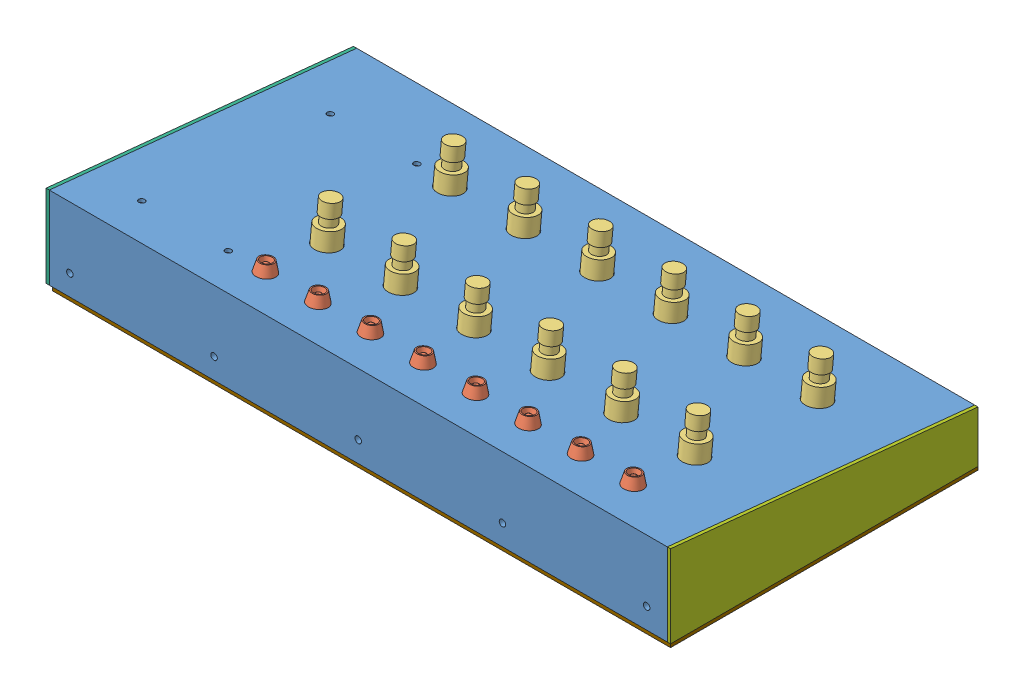
SolidWorks assembly case, configuration Défaut. Lengths in mm.
Overall size (305.42 59.42 149.25).
30 component instances, 9 part files, 75 mates.
Components (placement in the parent):
- top-1: top [Défaut] at (-137.6101 7.1938 300) size (300 40 149.25)
- led_red-1: led_red [Défaut] at (74.8899 20.7656 306.4982) x (-0.818284 -0.057481 -0.571933) z (0 0.994987 -0.1) size (9.2 9.2 35)
- led_red-2: led_red [Défaut] at (125.8899 20.7656 306.4982) x (-0.818284 -0.057481 -0.571933) z (0 0.994987 -0.1) size (9.2 9.2 35)
- led_red-3: led_red [Défaut] at (-27.1101 20.7656 306.4982) x (-0.818284 -0.057481 -0.571933) z (0 0.994987 -0.1) size (9.2 9.2 35)
- led_red-4: led_red [Défaut] at (-1.6101 20.7656 306.4982) x (-0.818284 -0.057481 -0.571933) z (0 0.994987 -0.1) size (9.2 9.2 35)
- led_red-5: led_red [Défaut] at (-52.6101 20.7656 306.4982) x (-0.818284 -0.057481 -0.571933) z (0 0.994987 -0.1) size (9.2 9.2 35)
- led_red-6: led_red [Défaut] at (49.3899 20.7656 306.4982) x (-0.818284 -0.057481 -0.571933) z (0 0.994987 -0.1) size (9.2 9.2 35)
- led_red-7: led_red [Défaut] at (100.3899 20.7656 306.4982) x (-0.818284 -0.057481 -0.571933) z (0 0.994987 -0.1) size (9.2 9.2 35)
- led_red-8: led_red [Défaut] at (23.8899 20.7656 306.4982) x (-0.818284 -0.057481 -0.571933) z (0 0.994987 -0.1) size (9.2 9.2 35)
- sw-1: sw [Défaut] at (125.8899 16.5526 280.454) x (1 0 0) z (0 -0.994987 0.1) size (13.3 30.3 33.85)
- sw-2: sw [Défaut] at (54.4899 10.5526 220.7547) x (1 0 0) z (0 -0.994987 0.1) size (13.3 30.3 33.85)
- sw-3: sw [Défaut] at (-16.9101 16.5526 280.454) x (1 0 0) z (0 -0.994987 0.1) size (13.3 30.3 33.85)
- sw-4: sw [Défaut] at (54.4899 16.5526 280.454) x (1 0 0) z (0 -0.994987 0.1) size (13.3 30.3 33.85)
- sw-5: sw [Défaut] at (90.1899 10.5526 220.7547) x (1 0 0) z (0 -0.994987 0.1) size (13.3 30.3 33.85)
- sw-6: sw [Défaut] at (-52.6101 16.5526 280.454) x (1 0 0) z (0 -0.994987 0.1) size (13.3 30.3 33.85)
- sw-7: sw [Défaut] at (90.1899 16.5526 280.454) x (1 0 0) z (0 -0.994987 0.1) size (13.3 30.3 33.85)
- sw-8: sw [Défaut] at (18.7899 10.5526 220.7547) x (1 0 0) z (0 -0.994987 0.1) size (13.3 30.3 33.85)
- sw-9: sw [Défaut] at (125.8899 10.5526 220.7547) x (1 0 0) z (0 -0.994987 0.1) size (13.3 30.3 33.85)
- sw-10: sw [Défaut] at (18.7899 16.5526 280.454) x (1 0 0) z (0 -0.994987 0.1) size (13.3 30.3 33.85)
- sw-11: sw [Défaut] at (-16.9101 10.5526 220.7547) x (1 0 0) z (0 -0.994987 0.1) size (13.3 30.3 33.85)
- sw-12: sw [Défaut] at (-52.6101 10.5526 220.7547) x (1 0 0) z (0 -0.994987 0.1) size (13.3 30.3 33.85)
- standoff_m3_10mm-1: standoff_m3_10mm [Défaut] at (-112.6101 9.9861 215.1181) x (1 0 0) z (0 -0.994987 0.1) size (5.2 4.5 10)
- standoff_m3_10mm-2: standoff_m3_10mm [Défaut] at (-112.6101 19.1861 306.657) x (1 0 0) z (0 -0.994987 0.1) size (5.2 4.5 10)
- standoff_m3_10mm-3: standoff_m3_10mm [Défaut] at (-70.6101 19.1861 306.657) x (1 0 0) z (0 -0.994987 0.1) size (5.2 4.5 10)
- standoff_m3_10mm-4: standoff_m3_10mm [Défaut] at (-70.6101 9.9861 215.1181) x (1 0 0) z (0 -0.994987 0.1) size (5.2 4.5 10)
- pcb-1: pcb [Défaut] at (-91.6101 4.6362 261.8875) x (0 -0.1 -0.994987) z (0 -0.994987 0.1) size (100 50 21.6)
- side_right-1: side_right [Défaut] at (-139.1976 -17.2344 177.1499) x (0 0 -1) z (1 0 0) size (149.25 40 1.59)
- side_left-1: side_left [Défaut] at (162.3899 -17.2344 177.1499) x (0 0 -1) z (1 0 0) size (149.25 40 1.59)
- dsub-9-1: dsub-9 [Défaut] at (-165.0011 -8.2344 294.9048) x (0 0 -1) z (1 0 0) size (30.81 12.55 16.87)
- bottom-1: bottom [Défaut] at (-3.6127 -18.8219 253.4547) x (1 0 0) z (0 1 0) size (300 149.25 1.59)
Mates (geometry in assembly coordinates):
- Coïncidente1: coincident: plane of led_red-4 through (-1.6101 20.7656 306.4982) normal (0 -0.994987 0.1); plane of led_red-5 through (-52.6101 20.7656 306.4982) normal (0 -0.994987 0.1)
- Coïncidente2: coincident: plane of led_red-3 through (-27.1101 20.7656 306.4982) normal (0 -0.994987 0.1); plane of led_red-5 through (-52.6101 20.7656 306.4982) normal (0 -0.994987 0.1)
- Coïncidente3: coincident: plane of led_red-1 through (74.8899 20.7656 306.4982) normal (0 -0.994987 0.1); plane of led_red-5 through (-52.6101 20.7656 306.4982) normal (0 -0.994987 0.1)
- Coïncidente4: coincident: plane of led_red-2 through (125.8899 20.7656 306.4982) normal (0 -0.994987 0.1); plane of led_red-5 through (-52.6101 20.7656 306.4982) normal (0 -0.994987 0.1)
- Coïncidente5: coincident: plane of led_red-5 through (-52.6101 20.7656 306.4982) normal (0 -0.994987 0.1); plane of led_red-6 through (49.3899 20.7656 306.4982) normal (0 -0.994987 0.1)
- Coïncidente6: coincident: plane of led_red-5 through (-52.6101 20.7656 306.4982) normal (0 -0.994987 0.1); plane of led_red-7 through (100.3899 20.7656 306.4982) normal (0 -0.994987 0.1)
- Coïncidente7: coincident: plane of led_red-5 through (-52.6101 20.7656 306.4982) normal (0 -0.994987 0.1); plane of led_red-8 through (23.8899 20.7656 306.4982) normal (0 -0.994987 0.1)
- Coïncidente8: coincident: plane of top-1 through (162.3899 22.7656 326.398) normal (0 0.994987 -0.1); plane of led_red-5 through (-52.6101 20.7656 306.4982) normal (0 -0.994987 0.1)
- Coaxiale1: concentric: cylinder of top-1 through (-52.6101 -18.8355 310.4783) axis (0 0.994987 -0.1) radius 4; cylinder of led_red-5 through (-52.6101 -9.084 309.4982) axis (0 0.994987 -0.1) radius 3.85
- Coaxiale2: concentric: cylinder of top-1 through (-27.1101 -18.8355 310.4783) axis (0 0.994987 -0.1) radius 4; cylinder of led_red-3 through (-27.1101 -9.084 309.4982) axis (0 0.994987 -0.1) radius 3.85
- Coaxiale3: concentric: cylinder of top-1 through (-1.6101 -18.8355 310.4783) axis (0 0.994987 -0.1) radius 4; cylinder of led_red-4 through (-1.6101 -9.084 309.4982) axis (0 0.994987 -0.1) radius 3.85
- Coaxiale4: concentric: cylinder of top-1 through (23.8899 -18.8355 310.4783) axis (0 0.994987 -0.1) radius 4; cylinder of led_red-8 through (23.8899 -9.084 309.4982) axis (0 0.994987 -0.1) radius 3.85
- Coaxiale5: concentric: cylinder of top-1 through (49.3899 -18.8355 310.4783) axis (0 0.994987 -0.1) radius 4; cylinder of led_red-6 through (49.3899 -9.084 309.4982) axis (0 0.994987 -0.1) radius 3.85
- Coaxiale6: concentric: cylinder of top-1 through (74.8899 -18.8355 310.4783) axis (0 0.994987 -0.1) radius 4; cylinder of led_red-1 through (74.8899 -9.084 309.4982) axis (0 0.994987 -0.1) radius 3.85
- Coaxiale7: concentric: cylinder of top-1 through (100.3899 -18.8355 310.4783) axis (0 0.994987 -0.1) radius 4; cylinder of led_red-7 through (100.3899 -9.084 309.4982) axis (0 0.994987 -0.1) radius 3.85
- Coaxiale8: concentric: cylinder of top-1 through (125.8899 -18.8355 310.4783) axis (0 0.994987 -0.1) radius 4; cylinder of led_red-2 through (125.8899 -9.084 309.4982) axis (0 0.994987 -0.1) radius 3.85
- Coïncidente9: coincident: plane of sw-1 through (125.8899 16.5526 280.454) normal (0 0.994987 -0.1); plane of sw-2 through (54.4899 10.5526 220.7547) normal (0 0.994987 -0.1)
- Coïncidente10: coincident: plane of sw-1 through (125.8899 16.5526 280.454) normal (0 0.994987 -0.1); plane of sw-3 through (-16.9101 16.5526 280.454) normal (0 0.994987 -0.1)
- Coïncidente11: coincident: plane of sw-1 through (125.8899 16.5526 280.454) normal (0 0.994987 -0.1); plane of sw-4 through (54.4899 16.5526 280.454) normal (0 0.994987 -0.1)
- Coïncidente12: coincident: plane of sw-1 through (125.8899 16.5526 280.454) normal (0 0.994987 -0.1); plane of sw-5 through (90.1899 10.5526 220.7547) normal (0 0.994987 -0.1)
- Coïncidente13: coincident: plane of sw-1 through (125.8899 16.5526 280.454) normal (0 0.994987 -0.1); plane of sw-6 through (-52.6101 16.5526 280.454) normal (0 0.994987 -0.1)
- Coïncidente14: coincident: plane of sw-1 through (125.8899 16.5526 280.454) normal (0 0.994987 -0.1); plane of sw-7 through (90.1899 16.5526 280.454) normal (0 0.994987 -0.1)
- Coïncidente15: coincident: plane of sw-1 through (125.8899 16.5526 280.454) normal (0 0.994987 -0.1); plane of sw-8 through (18.7899 10.5526 220.7547) normal (0 0.994987 -0.1)
- Coïncidente16: coincident: plane of sw-1 through (125.8899 16.5526 280.454) normal (0 0.994987 -0.1); plane of sw-9 through (125.8899 10.5526 220.7547) normal (0 0.994987 -0.1)
- Coïncidente17: coincident: plane of sw-1 through (125.8899 16.5526 280.454) normal (0 0.994987 -0.1); plane of sw-10 through (18.7899 16.5526 280.454) normal (0 0.994987 -0.1)
- Coïncidente18: coincident: plane of sw-1 through (125.8899 16.5526 280.454) normal (0 0.994987 -0.1); plane of sw-11 through (-16.9101 10.5526 220.7547) normal (0 0.994987 -0.1)
- Coïncidente19: coincident: plane of sw-1 through (125.8899 16.5526 280.454) normal (0 0.994987 -0.1); plane of sw-12 through (-52.6101 10.5526 220.7547) normal (0 0.994987 -0.1)
- Coïncidente21: coincident: plane of top-1 through (162.3899 6.3297 178.7374) normal (0 -0.994987 0.1); plane of sw-1 through (125.8899 16.5526 280.454) normal (0 0.994987 -0.1)
- Coaxiale9: concentric: cylinder of top-1 through (125.8899 -21.8355 280.6287) axis (0 0.994987 -0.1) radius 6; cylinder of sw-1 through (125.8899 26.1359 275.8073) axis (0 -0.994987 0.1) radius 5.805
- Coaxiale10: concentric: cylinder of top-1 through (125.8899 -27.8355 220.9294) axis (0 0.994987 -0.1) radius 6; cylinder of sw-9 through (125.8899 20.1359 216.1081) axis (0 -0.994987 0.1) radius 5.805
- Coaxiale11: concentric: cylinder of top-1 through (90.1899 -21.8355 280.6287) axis (0 0.994987 -0.1) radius 6; cylinder of sw-7 through (90.1899 26.1359 275.8073) axis (0 -0.994987 0.1) radius 5.805
- Coaxiale12: concentric: cylinder of top-1 through (54.4899 -21.8355 280.6287) axis (0 0.994987 -0.1) radius 6; cylinder of sw-4 through (54.4899 26.1359 275.8073) axis (0 -0.994987 0.1) radius 5.805
- Coaxiale13: concentric: cylinder of top-1 through (18.7899 -21.8355 280.6287) axis (0 0.994987 -0.1) radius 6; cylinder of sw-10 through (18.7899 26.1359 275.8073) axis (0 -0.994987 0.1) radius 5.805
- Coaxiale14: concentric: cylinder of top-1 through (-16.9101 -21.8355 280.6287) axis (0 0.994987 -0.1) radius 6; cylinder of sw-3 through (-16.9101 26.1359 275.8073) axis (0 -0.994987 0.1) radius 5.805
- Coaxiale15: concentric: cylinder of top-1 through (-52.6101 -21.8355 280.6287) axis (0 0.994987 -0.1) radius 6; cylinder of sw-6 through (-52.6101 26.1359 275.8073) axis (0 -0.994987 0.1) radius 5.805
- Coaxiale16: concentric: cylinder of top-1 through (90.1899 -27.8355 220.9294) axis (0 0.994987 -0.1) radius 6; cylinder of sw-5 through (90.1899 20.1359 216.1081) axis (0 -0.994987 0.1) radius 5.805
- Coaxiale17: concentric: cylinder of top-1 through (54.4899 -27.8355 220.9294) axis (0 0.994987 -0.1) radius 6; cylinder of sw-2 through (54.4899 20.1359 216.1081) axis (0 -0.994987 0.1) radius 5.805
- Coaxiale18: concentric: cylinder of top-1 through (18.7899 -27.8355 220.9294) axis (0 0.994987 -0.1) radius 6; cylinder of sw-8 through (18.7899 20.1359 216.1081) axis (0 -0.994987 0.1) radius 5.805
- Coaxiale19: concentric: cylinder of top-1 through (-16.9101 -27.8355 220.9294) axis (0 0.994987 -0.1) radius 6; cylinder of sw-11 through (-16.9101 20.1359 216.1081) axis (0 -0.994987 0.1) radius 5.805
- Coaxiale20: concentric: cylinder of top-1 through (-52.6101 -27.8355 220.9294) axis (0 0.994987 -0.1) radius 6; cylinder of sw-12 through (-52.6101 20.1359 216.1081) axis (0 -0.994987 0.1) radius 5.805
- Parallèle24: parallel: plane of top-1 through (162.3899 7.1938 300) normal (1 0 0); plane of sw-1 through (132.5399 0.8547 258.2625) normal (1 0 0)
- Parallèle25: parallel: plane of top-1 through (162.3899 7.1938 300) normal (1 0 0); plane of sw-9 through (132.5399 -5.1453 198.5633) normal (1 0 0)
- Parallèle26: parallel: plane of top-1 through (162.3899 7.1938 300) normal (1 0 0); plane of sw-7 through (96.8399 0.8547 258.2625) normal (1 0 0)
- Parallèle27: parallel: plane of top-1 through (162.3899 7.1938 300) normal (1 0 0); plane of sw-5 through (96.8399 -5.1453 198.5633) normal (1 0 0)
- Parallèle28: parallel: plane of top-1 through (162.3899 7.1938 300) normal (1 0 0); plane of sw-2 through (61.1399 -5.1453 198.5633) normal (1 0 0)
- Parallèle29: parallel: plane of top-1 through (162.3899 7.1938 300) normal (1 0 0); plane of sw-4 through (61.1399 0.8547 258.2625) normal (1 0 0)
- Parallèle30: parallel: plane of top-1 through (162.3899 7.1938 300) normal (1 0 0); plane of sw-10 through (25.4399 0.8547 258.2625) normal (1 0 0)
- Parallèle31: parallel: plane of top-1 through (162.3899 7.1938 300) normal (1 0 0); plane of sw-8 through (25.4399 -5.1453 198.5633) normal (1 0 0)
- Parallèle32: parallel: plane of top-1 through (162.3899 7.1938 300) normal (1 0 0); plane of sw-11 through (-10.2601 -5.1453 198.5633) normal (1 0 0)
- Parallèle33: parallel: plane of top-1 through (162.3899 7.1938 300) normal (1 0 0); plane of sw-3 through (-10.2601 0.8547 258.2625) normal (1 0 0)
- Parallèle34: parallel: plane of top-1 through (162.3899 7.1938 300) normal (1 0 0); plane of sw-6 through (-45.9601 0.8547 258.2625) normal (1 0 0)
- Parallèle35: parallel: plane of top-1 through (162.3899 7.1938 300) normal (1 0 0); plane of sw-12 through (-45.9601 -5.1453 198.5633) normal (1 0 0)
- Coïncidente58: coincident: plane of standoff_m3_10mm-3 through (-70.6101 19.1861 306.657) normal (0 0.994987 -0.1); plane of standoff_m3_10mm-4 through (-70.6101 9.9861 215.1181) normal (0 0.994987 -0.1)
- Coïncidente59: coincident: plane of standoff_m3_10mm-2 through (-112.6101 19.1861 306.657) normal (0 0.994987 -0.1); plane of standoff_m3_10mm-4 through (-70.6101 9.9861 215.1181) normal (0 0.994987 -0.1)
- Coïncidente60: coincident: plane of standoff_m3_10mm-1 through (-112.6101 9.9861 215.1181) normal (0 0.994987 -0.1); plane of standoff_m3_10mm-4 through (-70.6101 9.9861 215.1181) normal (0 0.994987 -0.1)
- Coïncidente61: coincident: plane of top-1 through (162.3899 6.3297 178.7374) normal (0 -0.994987 0.1); plane of standoff_m3_10mm-4 through (-70.6101 9.9861 215.1181) normal (0 0.994987 -0.1)
- Coaxiale21: concentric: cylinder of top-1 through (-70.6101 -28.0355 218.9394) axis (0 0.994987 -0.1) radius 1.5; cylinder of standoff_m3_10mm-4 through (-70.6101 0.0362 216.1181) axis (0 0.994987 -0.1) radius 1.5
- Coaxiale22: concentric: cylinder of top-1 through (-112.6101 -28.0355 218.9394) axis (0 0.994987 -0.1) radius 1.5; cylinder of standoff_m3_10mm-1 through (-112.6101 0.0362 216.1181) axis (0 0.994987 -0.1) radius 1.5
- Coaxiale23: concentric: cylinder of top-1 through (-112.6101 -18.8355 310.4783) axis (0 0.994987 -0.1) radius 1.5; cylinder of standoff_m3_10mm-2 through (-112.6101 9.2362 307.657) axis (0 0.994987 -0.1) radius 1.5
- Coaxiale24: concentric: cylinder of top-1 through (-70.6101 -18.8355 310.4783) axis (0 0.994987 -0.1) radius 1.5; cylinder of standoff_m3_10mm-3 through (-70.6101 9.2362 307.657) axis (0 0.994987 -0.1) radius 1.5
- Coïncidente62: coincident: plane of standoff_m3_10mm-4 through (-70.6101 0.0362 216.1181) normal (0 -0.994987 0.1); plane of pcb-1 through (-91.6101 4.6362 261.8875) normal (0 0.994987 -0.1)
- Coaxiale27: concentric: cylinder of standoff_m3_10mm-3 through (-70.6101 9.2362 307.657) axis (0 0.994987 -0.1) radius 1.5; cylinder of pcb-1 through (-70.6101 7.6442 307.817) axis (0 0.994987 -0.1) radius 1.6
- Coaxiale28: concentric: cylinder of standoff_m3_10mm-4 through (-70.6101 0.0362 216.1181) axis (0 0.994987 -0.1) radius 1.5; cylinder of pcb-1 through (-70.6101 -1.5558 216.2781) axis (0 0.994987 -0.1) radius 1.6
- Coïncidente63: coincident: plane of top-1 through (162.3899 7.1938 300) normal (1 0 0); plane of side_left-1 through (162.3899 -17.2344 177.1499) normal (-1 0 0)
- Coïncidente65: coincident: plane of top-1 through (162.3899 -17.2344 326.398) normal (0 0 1); plane of side_left-1 through (163.9774 22.7656 326.398) normal (0 0 1)
- Coïncidente66: coincident: plane of top-1 through (162.3899 -17.2344 324.8105) normal (0 -1 0); plane of side_left-1 through (163.9774 -17.2344 326.398) normal (0 -1 0)
- Coïncidente67: coincident: plane of top-1 through (-137.6101 7.1938 300) normal (-1 0 0); plane of side_right-1 through (-137.6101 -17.2344 177.1499) normal (1 0 0)
- Coïncidente68: coincident: plane of top-1 through (162.3899 -17.2344 326.398) normal (0 0 1); plane of side_right-1 through (-137.6101 22.7656 326.398) normal (0 0 1)
- Coïncidente69: coincident: plane of top-1 through (162.3899 -17.2344 324.8105) normal (0 -1 0); line of side_right-1 through (-139.1976 -17.2344 326.398) axis (0 0 -1)
- Coïncidente70: coincident: plane of side_right-1 through (-137.6101 -17.2344 177.1499) normal (1 0 0); plane of dsub-9-1 through (-137.6101 -8.2344 294.9048) normal (-1 0 0)
- Coaxiale29: concentric: cylinder of side_right-1 through (-137.6101 -8.2344 282.408) axis (-1 0 0) radius 1.59; cylinder of dsub-9-1 through (-136.3401 -8.2344 282.408) axis (1 0 0) radius 1.524
- Parallèle36: parallel: cylinder of side_right-1 through (-137.6101 -8.2344 307.398) axis (-1 0 0) radius 1.59; cylinder of dsub-9-1 through (-136.3401 -8.2344 307.4016) axis (1 0 0) radius 1.524
- Coïncidente71: coincident: plane of top-1 through (162.3899 -17.2344 177.1499) normal (0 -1 0); plane of bottom-1 through (-3.6127 -17.2344 253.4547) normal (0 1 0)
- Coïncidente72: coincident: plane of top-1 through (162.3899 -17.2344 326.398) normal (0 0 1); line of bottom-1 through (-136.0226 -17.2344 326.398) axis (1 0 0)
- Coïncidente73: coincident: plane of side_left-1 through (163.9774 -17.2344 177.1499) normal (1 0 0); line of bottom-1 through (163.9774 -18.8219 326.398) axis (0 0 -1)
